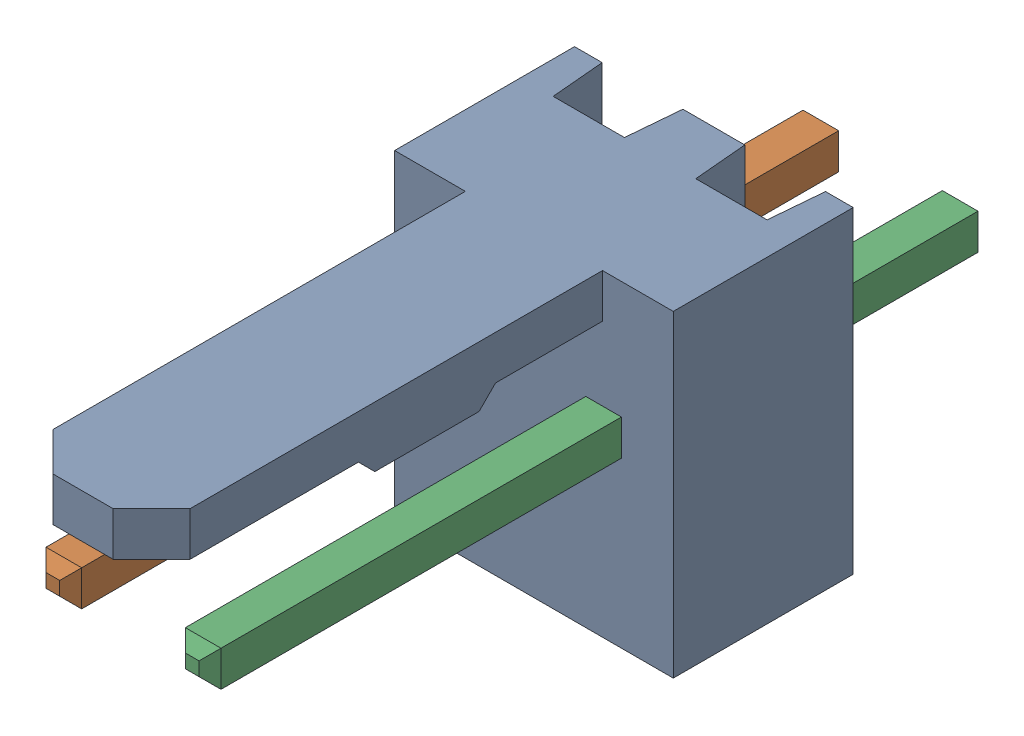
SolidWorks assembly Molex PCB 2 pin v2_7, configuration Predeterminado. Lengths in mm.
Overall size (5.08 5.79 14.92).
3 component instances, 2 part files, 0 mates.
Components (placement in the parent):
- BASE9710016_1-1: BASE9710016_1 [Predeterminado] at (2.54 2.895 -8.22) size (5.08 5.79 11.5)
- PINO9710016_1-1: PINO9710016_1 [Predeterminado] at (1.27 3.325 -0.72) size (0.65 0.65 14.2)
- PINO9710016_1-2: PINO9710016_1 [Predeterminado] at (3.81 3.325 -0.72) size (0.65 0.65 14.2)
